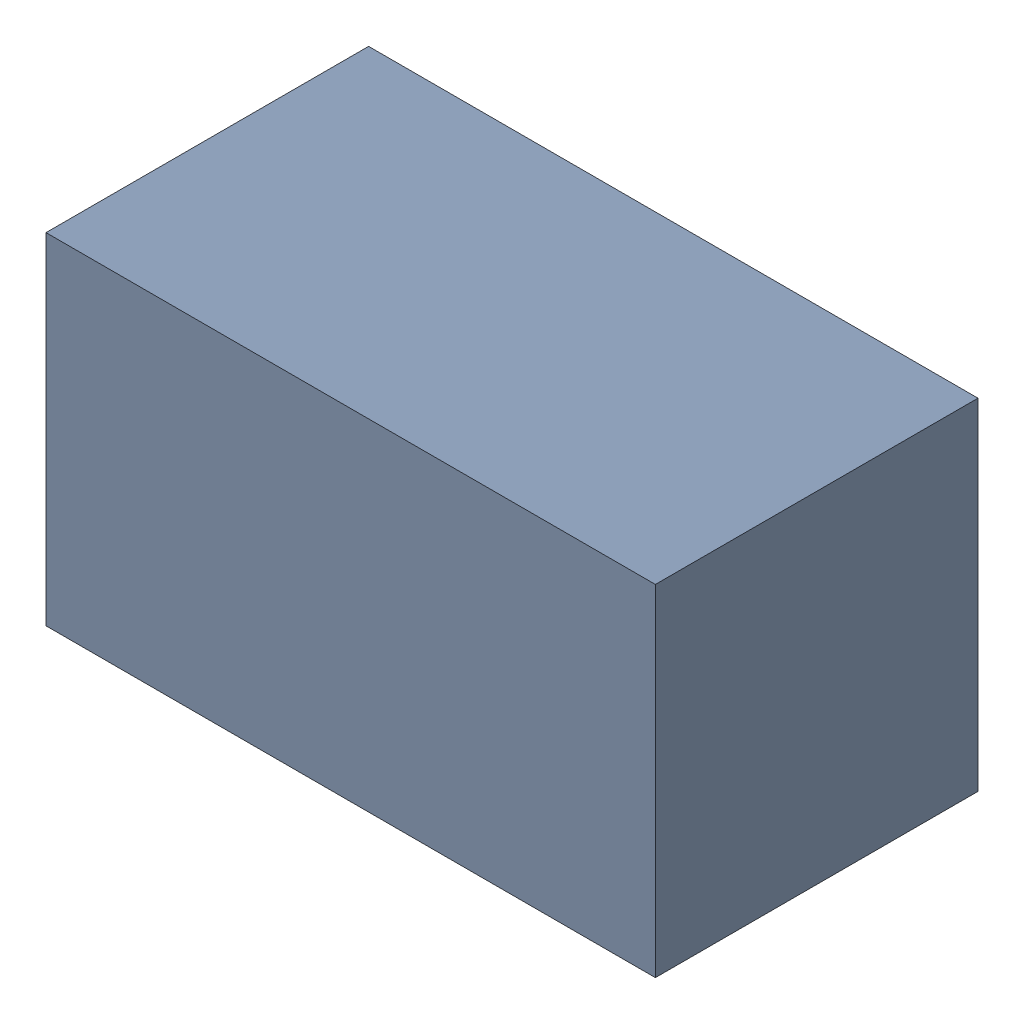
SolidWorks assembly D1, configuration Default. Lengths in mm.
Overall size (1.7 0.95 0.9).
2 component instances, 1 part files, 0 mates.
Components (placement in the parent):
- 580483600-1: 580483600 [Default] at (147.078 286.385 0) size (1.7 0.95 0.9)
  - Extruded_3-1: Extruded_3 [Default] at origin size (1.7 0.95 0.9)
